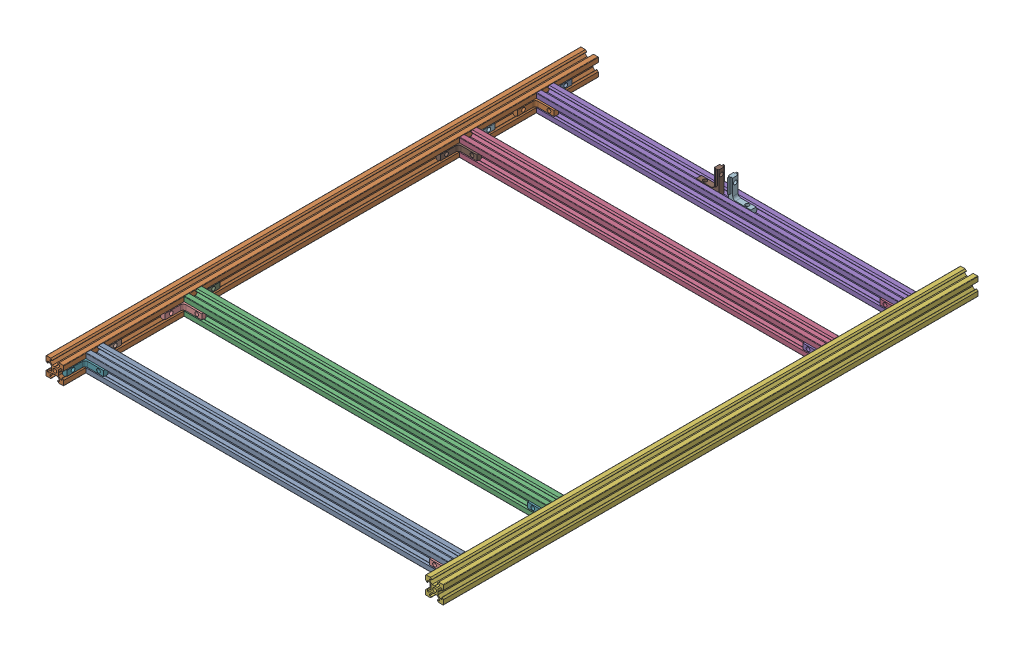
SolidWorks assembly frame_base_assembly, configuration Default. Lengths in mm.
Overall size (449 40.45 604).
24 component instances, 3 part files, 0 mates.
Components (placement in the parent):
- 409mm_2020_tslot_extrusion-1: 409mm_2020_tslot_extrusion [Default] at (0 -350 509) size (409 20 20)
- 604mm_2020_tslot_extrusion-1: 604mm_2020_tslot_extrusion [Default] at (0 -350 0) size (20 20 604)
- 409mm_2020_tslot_extrusion-2: 409mm_2020_tslot_extrusion [Default] at (0 -350 398) size (409 20 20)
- 409mm_2020_tslot_extrusion-3: 409mm_2020_tslot_extrusion [Default] at (0 -350 87) size (409 20 20)
- 409mm_2020_tslot_extrusion-4: 409mm_2020_tslot_extrusion [Default] at (0 -350 0) size (409 20 20)
- 604mm_2020_tslot_extrusion-2: 604mm_2020_tslot_extrusion [Default] at (429 -350 0) size (20 20 604)
- inside_hidden_corner_bracket-1: inside_hidden_corner_bracket [Default] at (4.45 -350 -29.6) x (0 0 1) z (0 1 0) size (25.5 26 10.4)
- inside_hidden_corner_bracket-2: inside_hidden_corner_bracket [Default] at (4.45 -350 -40.4) x (0 0 -1) z (0 -1 0) size (25.5 26 10.4)
- inside_hidden_corner_bracket-3: inside_hidden_corner_bracket [Default] at (4.45 -350 -151.4) x (0 0 -1) z (0 -1 0) size (25.5 26 10.4)
- inside_hidden_corner_bracket-4: inside_hidden_corner_bracket [Default] at (4.45 -350 -140.6) x (0 0 1) z (0 1 0) size (25.5 26 10.4)
- inside_hidden_corner_bracket-5: inside_hidden_corner_bracket [Default] at (4.45 -350 -451.6) x (0 0 1) z (0 1 0) size (25.5 26 10.4)
- inside_hidden_corner_bracket-6: inside_hidden_corner_bracket [Default] at (4.45 -350 -462.4) x (0 0 -1) z (0 -1 0) size (25.5 26 10.4)
- inside_hidden_corner_bracket-7: inside_hidden_corner_bracket [Default] at (4.45 -350 -549.4) x (0 0 -1) z (0 -1 0) size (25.5 26 10.4)
- inside_hidden_corner_bracket-8: inside_hidden_corner_bracket [Default] at (4.45 -350 -538.6) x (0 0 1) z (0 1 0) size (25.5 26 10.4)
- inside_hidden_corner_bracket-9: inside_hidden_corner_bracket [Default] at (424.55 -350 -549.4) x (0 0 -1) z (0 1 0) size (25.5 26 10.4)
- inside_hidden_corner_bracket-10: inside_hidden_corner_bracket [Default] at (424.55 -350 -538.6) x (0 0 1) z (0 -1 0) size (25.5 26 10.4)
- inside_hidden_corner_bracket-11: inside_hidden_corner_bracket [Default] at (424.55 -350 -451.6) x (0 0 1) z (0 -1 0) size (25.5 26 10.4)
- inside_hidden_corner_bracket-12: inside_hidden_corner_bracket [Default] at (424.55 -350 -462.4) x (0 0 -1) z (0 1 0) size (25.5 26 10.4)
- inside_hidden_corner_bracket-13: inside_hidden_corner_bracket [Default] at (424.55 -350 -140.6) x (0 0 1) z (0 -1 0) size (25.5 26 10.4)
- inside_hidden_corner_bracket-14: inside_hidden_corner_bracket [Default] at (424.55 -350 -151.4) x (0 0 -1) z (0 1 0) size (25.5 26 10.4)
- inside_hidden_corner_bracket-15: inside_hidden_corner_bracket [Default] at (424.55 -350 -40.4) x (0 0 -1) z (0 1 0) size (25.5 26 10.4)
- inside_hidden_corner_bracket-16: inside_hidden_corner_bracket [Default] at (424.55 -350 -29.6) x (0 0 1) z (0 -1 0) size (25.5 26 10.4)
- inside_hidden_corner_bracket-17: inside_hidden_corner_bracket [Default] at (209.1 -345.55 -544) x (-1 0 0) z (0 0 -1) size (25.5 26 10.4)
- inside_hidden_corner_bracket-18: inside_hidden_corner_bracket [Default] at (219.9 -345.55 -544) size (25.5 26 10.4)
